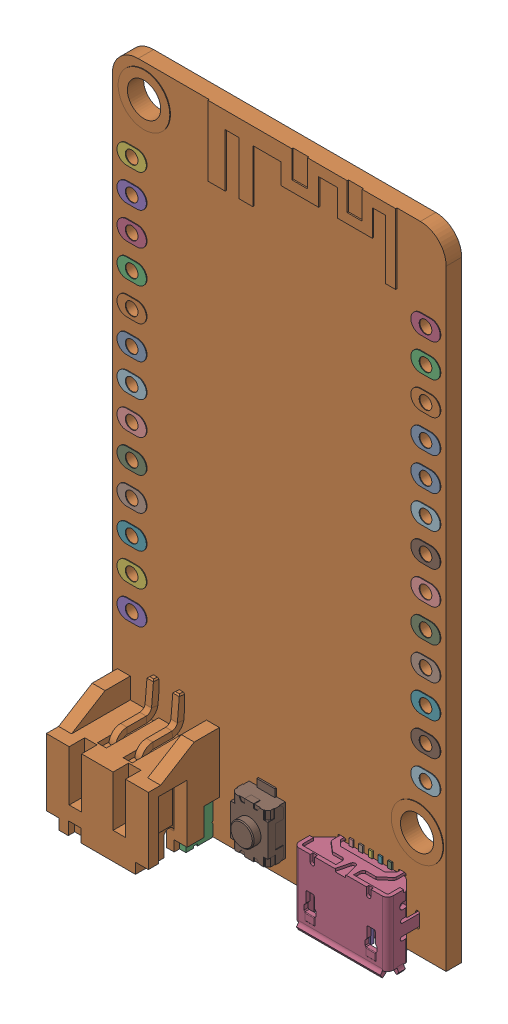
SolidWorks assembly Component1, configuration Standard. Lengths in mm.
Overall size (25.85 49.76 6.72).
31 component instances, 31 part files, 0 mates.
Components (placement in the parent):
- JST-S2B-PH-SM4-TB-1: JST-S2B-PH-SM4-TB [Standard] at (7.55 1.4517 1.0983) x (-1 0 0) z (0 1 0) size (7.9 5.61 8.61)
- MicroUSB v1-1: MicroUSB v1 [Standard] at (20.1 5.0215 2.3782) x (1 0 0) z (0 -1 0) size (7.56 3.45 5.78)
- 3x4x2 tact button v1-1: 3x4x2 tact button v1 [Standard] at (12.7088 5.744 1.2) x (0 -1 0) z (-1 0 0) size (5 2 2.9)
- Component2-1: Component2 [Standard] at origin size (25.02 31.95 0.05)
- Component1-0-1: Component1-0 [Standard] at origin size (25.85 49.3 1.31)
- Component1-1-1: Component1-1 [Standard] at origin size (2.29 1.45 0.01)
- Component1-2-1: Component1-2 [Standard] at origin size (2.29 1.45 0.01)
- Component1-3-1: Component1-3 [Standard] at origin size (2.29 1.45 0.01)
- Component1-4-1: Component1-4 [Standard] at origin size (2.29 1.45 0.01)
- Component1-5-1: Component1-5 [Standard] at origin size (2.29 1.45 0.01)
- Component1-6-1: Component1-6 [Standard] at origin size (2.29 1.45 0.01)
- Component1-7-1: Component1-7 [Standard] at origin size (2.29 1.45 0.01)
- Component1-8-1: Component1-8 [Standard] at origin size (2.29 1.45 0.01)
- Component1-9-1: Component1-9 [Standard] at origin size (2.29 1.45 0.01)
- Component1-10-1: Component1-10 [Standard] at origin size (2.29 1.45 0.01)
- Component1-11-1: Component1-11 [Standard] at origin size (2.29 1.45 0.01)
- Component1-12-1: Component1-12 [Standard] at origin size (2.29 1.45 0.01)
- Component1-13-1: Component1-13 [Standard] at origin size (2.29 1.45 0.01)
- Component1-14-1: Component1-14 [Standard] at origin size (2.29 1.45 0.01)
- Component1-15-1: Component1-15 [Standard] at origin size (2.29 1.45 0.01)
- Component1-16-1: Component1-16 [Standard] at origin size (2.29 1.45 0.01)
- Component1-17-1: Component1-17 [Standard] at origin size (2.29 1.45 0.01)
- Component1-18-1: Component1-18 [Standard] at origin size (2.29 1.45 0.01)
- Component1-19-1: Component1-19 [Standard] at origin size (2.29 1.45 0.01)
- Component1-20-1: Component1-20 [Standard] at origin size (2.29 1.45 0.01)
- Component1-21-1: Component1-21 [Standard] at origin size (2.29 1.45 0.01)
- Component1-22-1: Component1-22 [Standard] at origin size (2.29 1.45 0.01)
- Component1-23-1: Component1-23 [Standard] at origin size (2.29 1.45 0.01)
- Component1-24-1: Component1-24 [Standard] at origin size (2.29 1.45 0.01)
- Component1-25-1: Component1-25 [Standard] at origin size (2.29 1.45 0.01)
- Component1-26-1: Component1-26 [Standard] at origin size (2.29 1.45 0.01)
